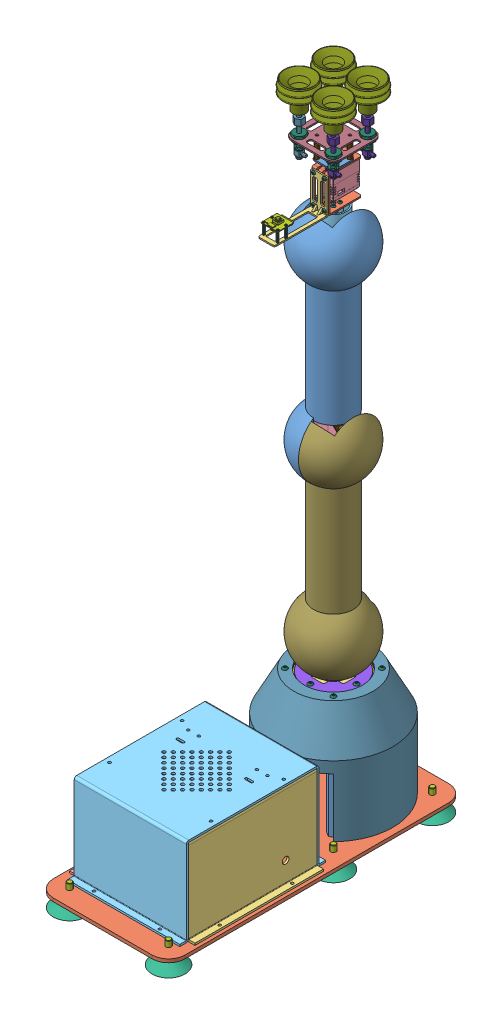
SolidWorks assembly 机械臂1.0, configuration 默认. Lengths in mm.
Overall size (254.56 964.15 483.5).
293 component instances, 44 part files, 11 mates.
Components (placement in the parent):
- 云台-1: 云台 [默认] at origin size (254.56 222.8 254.56) (flexible)
  - M8×100铜柱-1: M8×100铜柱 [默认] at (-52.0858 0 -53.9281) x (0 0 1) z (-1 0 0) size (15.01 100 13)
  - M8×100铜柱-2: M8×100铜柱 [默认] at (53.9802 0 -53.9281) x (0 0 1) z (-1 0 0) size (15.01 100 13)
  - M8×100铜柱-3: M8×100铜柱 [默认] at (53.9802 0 52.1379) x (0 0 1) z (-1 0 0) size (15.01 100 13)
  - M8×100铜柱-4: M8×100铜柱 [默认] at (-52.0858 0 52.1379) x (0 0 1) z (-1 0 0) size (15.01 100 13)
  - 6号舵机底座-1: 6号舵机底座 [默认] at (0 103 0) size (174 3 174)
  - 轴承底座-1: 轴承底座 [默认] at (0 148.8 0) x (-1 0 0) z (0 0 -1) size (82 2 84)
  - 舵机-1: 舵机 [默认] at (0 103 -9.65) x (0 0 1) z (-1 0 0) size (40 51.4 20)
  - 主舵盘-1: 主舵盘 [默认] at (0 143.8 0) x (0 0 1) z (-1 0 0) size (20 5 20)
  - 轴承外底座-1: 轴承外底座 [默认] at (0 148.8 0) x (0 0 1) z (-1 0 0) size (120 2 120)
  - 轴承-1: 轴承 [默认] at (0 148.8 0) x (-0.002471 0 0.999997) z (-0.999997 0 -0.002471) size (100 10 100)
  - 轴承顶-1: 轴承顶 [默认] at (0 160.8 0) x (-1 0 0) z (0 0 -1) size (84 2 84)
  - 轴承外顶-1: 轴承外顶 [默认] at (0 160.8 0) x (-1 0 0) z (0 0 -1) size (120 2 120)
  - 大U支架-1: 大U支架 [默认] at (0 182.8 0) x (-1 0 0) z (0 0 -1) size (51.6 42 40)
  - 镙丝 PA2x12-半圆头十字(自攻)-6: 镙丝 PA2x12-半圆头十字(自攻) [默认] at (-8 150 0) x (0.999316 0 -0.036972) z (0.036972 0 0.999316) size (3.55 13.42 3.55)
  - 镙丝 PA2x12-半圆头十字(自攻)-7: 镙丝 PA2x12-半圆头十字(自攻) [默认] at (-5.6569 150 -5.6569) x (0.776673 0 0.629905) z (-0.629905 0 0.776673) size (3.55 13.42 3.55)
  - 镙丝 PA2x12-半圆头十字(自攻)-8: 镙丝 PA2x12-半圆头十字(自攻) [默认] at (0 150 -8) x (0 0 1) z (-1 0 0) size (3.55 13.42 3.55)
  - 镙丝 PA2x12-半圆头十字(自攻)-9: 镙丝 PA2x12-半圆头十字(自攻) [默认] at (5.6569 150 -5.6569) x (0 0 1) z (-1 0 0) size (3.55 13.42 3.55)
  - 镙丝 PA2x12-半圆头十字(自攻)-10: 镙丝 PA2x12-半圆头十字(自攻) [默认] at (8 150 0) x (0 0 1) z (-1 0 0) size (3.55 13.42 3.55)
  - 镙丝 PA2x12-半圆头十字(自攻)-11: 镙丝 PA2x12-半圆头十字(自攻) [默认] at (5.6569 150 5.6569) x (0.961264 0 -0.275631) z (0.275631 0 0.961264) size (3.55 13.42 3.55)
  - 镙丝 PA2x12-半圆头十字(自攻)-12: 镙丝 PA2x12-半圆头十字(自攻) [默认] at (0 150 8) x (0.931957 0 -0.36257) z (0.36257 0 0.931957) size (3.55 13.42 3.55)
  - 镙丝 PA2x12-半圆头十字(自攻)-13: 镙丝 PA2x12-半圆头十字(自攻) [默认] at (-5.6569 150 5.6569) x (0.711428 0 -0.702759) z (0.702759 0 0.711428) size (3.55 13.42 3.55)
  - 镙丝 PA3x12-半圆头十字(自攻)-1: 镙丝 PA3x12-半圆头十字(自攻) [默认] at (0 150.8 0) x (0 0 1) z (-1 0 0) size (5.3 14.31 5.3)
  - 12号舵机连接管-1: 12号舵机连接管 [默认] at (0 160.8 0) x (0 0 1) z (-1 0 0) size (40 20 40)
  - 云台外壳-1: 云台外壳 [默认] at (0 160.8 0) x (0.707107 0 0.707107) z (-0.707107 0 0.707107) size (180 163.8 180)
  - hexagon socket button head screws gb-34: hexagon socket button head screws gb [GB_SOCKET_TYPE7 M4X16-N] at (35 163 0) x (0 -1 0) z (-1 0 0) size (18.2 7.6 7.6)
  - hexagon socket button head screws gb-35: hexagon socket button head screws gb [GB_SOCKET_TYPE7 M4X16-N] at (0 163 -35) x (0 -1 0) z (-1 0 0) size (18.2 7.6 7.6)
  - hexagon socket button head screws gb-36: hexagon socket button head screws gb [GB_SOCKET_TYPE7 M4X16-N] at (0 163 35) x (0 -1 0) z (-1 0 0) size (18.2 7.6 7.6)
  - hexagon socket button head screws gb-37: hexagon socket button head screws gb [GB_SOCKET_TYPE7 M4X16-N] at (-35 163 0) x (0 -1 0) z (-1 0 0) size (18.2 7.6 7.6)
  - hexagon socket button head screws gb-38: hexagon socket button head screws gb [GB_SOCKET_TYPE7 M4X16-N] at (36.7696 166 36.7696) x (0 -1 0) z (-1 0 0) size (18.2 7.6 7.6)
  - hexagon socket button head screws gb-39: hexagon socket button head screws gb [GB_SOCKET_TYPE7 M4X16-N] at (36.7696 166 -36.7696) x (0 -1 0) z (-1 0 0) size (18.2 7.6 7.6)
  - hexagon socket button head screws gb-40: hexagon socket button head screws gb [GB_SOCKET_TYPE7 M4X16-N] at (-36.7696 166 -36.7696) x (0 -1 0) z (-1 0 0) size (18.2 7.6 7.6)
  - hexagon socket button head screws gb-41: hexagon socket button head screws gb [GB_SOCKET_TYPE7 M4X16-N] at (-36.7696 166 36.7696) x (0 -1 0) z (-1 0 0) size (18.2 7.6 7.6)
  - hexagon socket button head screws gb-42: hexagon socket button head screws gb [GB_SOCKET_TYPE7 M4X16-N] at (5 185 5) x (0 -1 0) z (-1 0 0) size (18.2 7.6 7.6)
  - hexagon socket button head screws gb-43: hexagon socket button head screws gb [GB_SOCKET_TYPE7 M4X16-N] at (5 185 -5) x (0 -1 0) z (-1 0 0) size (18.2 7.6 7.6)
  - hexagon socket button head screws gb-44: hexagon socket button head screws gb [GB_SOCKET_TYPE7 M4X16-N] at (-5 185 5) x (0 -1 0) z (-1 0 0) size (18.2 7.6 7.6)
  - hexagon socket button head screws gb-45: hexagon socket button head screws gb [GB_SOCKET_TYPE7 M4X16-N] at (-5 185 -5) x (0 -1 0) z (-1 0 0) size (18.2 7.6 7.6)
  - hexagon socket button head screws gb-47: hexagon socket button head screws gb [GB_SOCKET_TYPE7 M8X40-N] at (-53.033 110.4 -53.033) x (0 -1 0) z (-1 0 0) size (44.4 14 14)
  - hexagon socket button head screws gb-48: hexagon socket button head screws gb [GB_SOCKET_TYPE7 M8X40-N] at (53.033 110.4 -53.033) x (0 -1 0) z (-1 0 0) size (44.4 14 14)
  - hexagon socket button head screws gb-49: hexagon socket button head screws gb [GB_SOCKET_TYPE7 M8X40-N] at (53.033 110.4 53.033) x (0 -1 0) z (-1 0 0) size (44.4 14 14)
  - hexagon socket button head screws gb-50: hexagon socket button head screws gb [GB_SOCKET_TYPE7 M8X40-N] at (-53.033 110.4 53.033) x (0 -1 0) z (-1 0 0) size (44.4 14 14)
  - 镙丝 PM2x8-半圆头-1: 镙丝 PM2x8-半圆头 [默认] at (-8 98.8 -9.15) x (-0.546944 0 0.837169) z (0.837169 0 0.546944) size (3.55 9.32 3.55)
  - 镙丝 PM2x8-半圆头-2: 镙丝 PM2x8-半圆头 [默认] at (-7 98.8 -20.15) x (-0.546944 0 0.837169) z (0.837169 0 0.546944) size (3.55 9.32 3.55)
  - 镙丝 PM2x8-半圆头-3: 镙丝 PM2x8-半圆头 [默认] at (8 98.8 -9.15) x (-0.546944 0 0.837169) z (0.837169 0 0.546944) size (3.55 9.32 3.55)
  - 镙丝 PM2x8-半圆头-4: 镙丝 PM2x8-半圆头 [默认] at (7 98.8 -20.15) x (-0.546944 0 0.837169) z (0.837169 0 0.546944) size (3.55 9.32 3.55)
  - 镙丝 PM2x8-半圆头-5: 镙丝 PM2x8-半圆头 [默认] at (0 98.8 -27.15) x (-0.546944 0 0.837169) z (0.837169 0 0.546944) size (3.55 9.32 3.55)
- 机械臂-1: 机械臂 [默认] at (-53.1 220.673 0) x (0 0 -1) z (1 0 0) size (149.99 632.89 106) (flexible)
  - 舵机-2: 舵机 [默认] at (0 1.777 33.1) x (0 -1 0) z (-1 0 0) size (43.48 52.6 27.66) (flexible)
    - 舵机-1: 舵机 [默认] at origin size (40 51.4 20)
    - 副舵盘-1: 副舵盘 [默认] at (9.65 -0.8 0) x (-0.707107 0 -0.707107) z (-0.707107 0 0.707107) size (20 5 20)
    - 主舵盘-1: 主舵盘 [默认] at (9.65 40.8 0) x (-0.119517 0 0.992832) z (-0.992832 0 -0.119517) size (20 5 20)
  - 短U支架-1: 短U支架 [默认] at (0 29.777 53.1) x (0 0 1) z (1 0 0) size (44 22 40)
  - 舵机-3: 舵机 [默认] at (0 253.427 33.1) x (0 -1 0) z (-1 0 0) size (43.48 52.6 27.66) (flexible)
    - 舵机-1: 舵机 [默认] at origin size (40 51.4 20)
    - 副舵盘-1: 副舵盘 [默认] at (9.65 -0.8 0) x (0.998338 0 -0.057634) z (-0.057634 0 -0.998338) size (20 5 20)
    - 主舵盘-1: 主舵盘 [默认] at (9.65 40.8 0) x (-0.770235 0 -0.63776) z (0.63776 0 -0.770235) size (20 5 20)
  - 短U支架-2: 短U支架 [默认] at (0 281.427 53.1) x (0 0 1) z (1 0 0) size (44 22 40)
  - 120cm连接管-2: 120cm连接管 [默认] at (0 463.427 53.1) x (0 0 -1) z (-1 0 0) size (106 351.73 100.99)
  - 舵机-5: 舵机 [默认] at (0 505.077 33.1) x (0 -1 0) z (-1 0 0) size (43.48 52.6 27.66) (flexible)
    - 舵机-1: 舵机 [默认] at origin size (40 51.4 20)
    - 副舵盘-1: 副舵盘 [默认] at (9.65 -0.8 0) x (-0.661524 0 0.749924) z (0.749924 0 0.661524) size (20 5 20)
    - 主舵盘-1: 主舵盘 [默认] at (9.65 40.8 0) x (0.634107 0 -0.773246) z (0.773246 0 0.634107) size (20 5 20)
  - 短U支架-3: 短U支架 [默认] at (0 533.077 53.1) x (0 0 1) z (1 0 0) size (44 22 40)
  - 转向舵机支架-1: 转向舵机支架 [默认] at (-18 580.077 53.1) x (0 -1 0) z (0 0 -1) size (54 50.65 25)
  - 舵机-7: 舵机 [默认] at (9.65 565.077 53.1) x (-1 0 0) z (0 0 -1) size (40 51.4 20)
  - 主舵盘-1: 主舵盘 [默认] at (0 605.877 53.1) size (20 5 20)
  - 摄像头支架-1: 摄像头支架 [默认] at (-22 580.077 53.1) x (0 -1 0) z (0 0 -1) size (52 82 25)
  - 镙丝 PM2x4-半圆头-1: 镙丝 PM2x4-半圆头 [默认] at (-7 515.577 76.3) x (0.766466 0.642285 0) z (0.642285 -0.766466 0) size (3.55 5.35 3.55)
  - 镙丝 PM2x4-半圆头-2: 镙丝 PM2x4-半圆头 [默认] at (7 515.577 76.3) x (0.766466 0.642285 0) z (0.642285 -0.766466 0) size (3.55 5.35 3.55)
  - 镙丝 PM2x4-半圆头-3: 镙丝 PM2x4-半圆头 [默认] at (7 515.577 29.9) x (0.766466 0.642285 0) z (-0.642285 0.766466 0) size (3.55 5.35 3.55)
  - 镙丝 PM2x4-半圆头-4: 镙丝 PM2x4-半圆头 [默认] at (0 522.577 76.3) x (0.766466 0.642285 0) z (0.642285 -0.766466 0) size (3.55 5.35 3.55)
  - 镙丝 PM2x4-半圆头-5: 镙丝 PM2x4-半圆头 [默认] at (0 522.577 29.9) x (0.766466 0.642285 0) z (-0.642285 0.766466 0) size (3.55 5.35 3.55)
  - 镙丝 PM2x4-半圆头-6: 镙丝 PM2x4-半圆头 [默认] at (-7 515.577 29.9) x (0.766466 0.642285 0) z (-0.642285 0.766466 0) size (3.55 5.35 3.55)
  - 镙丝 PM2x4-半圆头-7: 镙丝 PM2x4-半圆头 [默认] at (-5.6569 489.7701 26.1) x (0.766466 0.642285 0) z (-0.642285 0.766466 0) size (3.55 5.35 3.55)
  - 镙丝 PM2x4-半圆头-8: 镙丝 PM2x4-半圆头 [默认] at (-8 495.427 26.1) x (0.766466 0.642285 0) z (-0.642285 0.766466 0) size (3.55 5.35 3.55)
  - 镙丝 PM2x4-半圆头-9: 镙丝 PM2x4-半圆头 [默认] at (0 503.427 26.1) x (0.766466 0.642285 0) z (-0.642285 0.766466 0) size (3.55 5.35 3.55)
  - 镙丝 PM2x4-半圆头-10: 镙丝 PM2x4-半圆头 [默认] at (-5.6569 501.0838 26.1) x (0.766466 0.642285 0) z (-0.642285 0.766466 0) size (3.55 5.35 3.55)
  - 镙丝 PM2x4-半圆头-11: 镙丝 PM2x4-半圆头 [默认] at (8 495.427 26.1) x (0.766466 0.642285 0) z (-0.642285 0.766466 0) size (3.55 5.35 3.55)
  - 镙丝 PM2x4-半圆头-12: 镙丝 PM2x4-半圆头 [默认] at (5.6569 501.0838 26.1) x (0.766466 0.642285 0) z (-0.642285 0.766466 0) size (3.55 5.35 3.55)
  - 镙丝 PM2x4-半圆头-13: 镙丝 PM2x4-半圆头 [默认] at (-8 495.427 80.1) x (0.766466 0.642285 0) z (0.642285 -0.766466 0) size (3.55 5.35 3.55)
  - 镙丝 PM2x4-半圆头-14: 镙丝 PM2x4-半圆头 [默认] at (0 487.427 80.1) x (0.766466 0.642285 0) z (0.642285 -0.766466 0) size (3.55 5.35 3.55)
  - 镙丝 PM2x4-半圆头-15: 镙丝 PM2x4-半圆头 [默认] at (-5.6569 489.7701 80.1) x (0.766466 0.642285 0) z (0.642285 -0.766466 0) size (3.55 5.35 3.55)
  - 镙丝 PM2x4-半圆头-16: 镙丝 PM2x4-半圆头 [默认] at (5.6569 489.7701 80.1) x (0.766466 0.642285 0) z (0.642285 -0.766466 0) size (3.55 5.35 3.55)
  - 镙丝 PM2x4-半圆头-17: 镙丝 PM2x4-半圆头 [默认] at (-5.6569 501.0838 80.1) x (0.766466 0.642285 0) z (0.642285 -0.766466 0) size (3.55 5.35 3.55)
  - 镙丝 PM2x4-半圆头-18: 镙丝 PM2x4-半圆头 [默认] at (0 503.427 80.1) x (0.766466 0.642285 0) z (0.642285 -0.766466 0) size (3.55 5.35 3.55)
  - 镙丝 PM2x4-半圆头-19: 镙丝 PM2x4-半圆头 [默认] at (20.15 608.277 60.1) x (0.530073 0 0.847952) z (-0.847952 0 0.530073) size (3.55 5.35 3.55)
  - 镙丝 PM2x4-半圆头-20: 镙丝 PM2x4-半圆头 [默认] at (20.15 608.277 46.1) x (0.530073 0 0.847952) z (-0.847952 0 0.530073) size (3.55 5.35 3.55)
  - 镙丝 PM2x4-半圆头-21: 镙丝 PM2x4-半圆头 [默认] at (9.15 608.277 45.1) x (-0.92142 0 0.388568) z (-0.388568 0 -0.92142) size (3.55 5.35 3.55)
  - 镙丝 PM2x4-半圆头-22: 镙丝 PM2x4-半圆头 [默认] at (27.15 608.277 53.1) x (0.530073 0 0.847952) z (-0.847952 0 0.530073) size (3.55 5.35 3.55)
  - 镙丝 PM2x4-半圆头-23: 镙丝 PM2x4-半圆头 [默认] at (9.15 608.277 61.1) x (0.530073 0 0.847952) z (-0.847952 0 0.530073) size (3.55 5.35 3.55)
  - 镙丝 PM2x4-半圆头-24: 镙丝 PM2x4-半圆头 [默认] at (7 263.927 29.9) x (0.766466 0.642285 0) z (-0.642285 0.766466 0) size (3.55 5.35 3.55)
  - 镙丝 PM2x4-半圆头-25: 镙丝 PM2x4-半圆头 [默认] at (0 270.927 29.9) x (0.766466 0.642285 0) z (-0.642285 0.766466 0) size (3.55 5.35 3.55)
  - 镙丝 PM2x4-半圆头-26: 镙丝 PM2x4-半圆头 [默认] at (-7 263.927 29.9) x (0.766466 0.642285 0) z (-0.642285 0.766466 0) size (3.55 5.35 3.55)
  - 镙丝 PM2x4-半圆头-27: 镙丝 PM2x4-半圆头 [默认] at (-5.6569 238.1201 26.1) x (0.766466 0.642285 0) z (-0.642285 0.766466 0) size (3.55 5.35 3.55)
  - 镙丝 PM2x4-半圆头-28: 镙丝 PM2x4-半圆头 [默认] at (-8 243.777 26.1) x (0.766466 0.642285 0) z (-0.642285 0.766466 0) size (3.55 5.35 3.55)
  - 镙丝 PM2x4-半圆头-29: 镙丝 PM2x4-半圆头 [默认] at (0 235.777 26.1) x (0.766466 0.642285 0) z (-0.642285 0.766466 0) size (3.55 5.35 3.55)
  - 镙丝 PM2x4-半圆头-30: 镙丝 PM2x4-半圆头 [默认] at (5.6569 238.1201 26.1) x (0.766466 0.642285 0) z (-0.642285 0.766466 0) size (3.55 5.35 3.55)
  - 镙丝 PM2x4-半圆头-31: 镙丝 PM2x4-半圆头 [默认] at (0 251.777 26.1) x (0.766466 0.642285 0) z (-0.642285 0.766466 0) size (3.55 5.35 3.55)
  - 镙丝 PM2x4-半圆头-32: 镙丝 PM2x4-半圆头 [默认] at (8 243.777 26.1) x (0.766466 0.642285 0) z (-0.642285 0.766466 0) size (3.55 5.35 3.55)
  - 镙丝 PM2x4-半圆头-33: 镙丝 PM2x4-半圆头 [默认] at (0 251.777 80.1) x (0.766466 0.642285 0) z (0.642285 -0.766466 0) size (3.55 5.35 3.55)
  - 镙丝 PM2x4-半圆头-34: 镙丝 PM2x4-半圆头 [默认] at (8 243.777 80.1) x (0.766466 0.642285 0) z (0.642285 -0.766466 0) size (3.55 5.35 3.55)
  - 镙丝 PM2x4-半圆头-35: 镙丝 PM2x4-半圆头 [默认] at (5.6569 238.1201 80.1) x (0.766466 0.642285 0) z (0.642285 -0.766466 0) size (3.55 5.35 3.55)
  - 镙丝 PM2x4-半圆头-36: 镙丝 PM2x4-半圆头 [默认] at (-5.6569 238.1201 80.1) x (0.766466 0.642285 0) z (0.642285 -0.766466 0) size (3.55 5.35 3.55)
  - 镙丝 PM2x4-半圆头-37: 镙丝 PM2x4-半圆头 [默认] at (0 235.777 80.1) x (0.766466 0.642285 0) z (0.642285 -0.766466 0) size (3.55 5.35 3.55)
  - 镙丝 PM2x4-半圆头-38: 镙丝 PM2x4-半圆头 [默认] at (5.6569 249.4338 80.1) x (0.766466 0.642285 0) z (0.642285 -0.766466 0) size (3.55 5.35 3.55)
  - 镙丝 PM2x4-半圆头-39: 镙丝 PM2x4-半圆头 [默认] at (-7 263.927 76.3) x (0.766466 0.642285 0) z (0.642285 -0.766466 0) size (3.55 5.35 3.55)
  - 镙丝 PM2x4-半圆头-40: 镙丝 PM2x4-半圆头 [默认] at (0 270.927 76.3) x (0.766466 0.642285 0) z (0.642285 -0.766466 0) size (3.55 5.35 3.55)
  - 镙丝 PM2x4-半圆头-41: 镙丝 PM2x4-半圆头 [默认] at (7 263.927 76.3) x (0.766466 0.642285 0) z (0.642285 -0.766466 0) size (3.55 5.35 3.55)
  - 镙丝 PM2x4-半圆头-42: 镙丝 PM2x4-半圆头 [默认] at (-7 12.277 76.3) x (0.766466 0.642285 0) z (0.642285 -0.766466 0) size (3.55 5.35 3.55)
  - 镙丝 PM2x4-半圆头-43: 镙丝 PM2x4-半圆头 [默认] at (0 19.277 76.3) x (0.766466 0.642285 0) z (0.642285 -0.766466 0) size (3.55 5.35 3.55)
  - 镙丝 PM2x4-半圆头-44: 镙丝 PM2x4-半圆头 [默认] at (7 12.277 76.3) x (0.766466 0.642285 0) z (0.642285 -0.766466 0) size (3.55 5.35 3.55)
  - 镙丝 PM2x4-半圆头-45: 镙丝 PM2x4-半圆头 [默认] at (-7.9427 -6.9169 78.1) x (0.766466 0.642285 0) z (0.642285 -0.766466 0) size (3.55 5.35 3.55)
  - 镙丝 PM2x4-半圆头-46: 镙丝 PM2x4-半圆头 [默认] at (-4.9402 -1.5807 78.1) x (0.766466 0.642285 0) z (0.642285 -0.766466 0) size (3.55 5.35 3.55)
  - 镙丝 PM2x4-半圆头-47: 镙丝 PM2x4-半圆头 [默认] at (-6.2924 -12.8133 78.1) x (0.766466 0.642285 0) z (0.642285 -0.766466 0) size (3.55 5.35 3.55)
  - 镙丝 PM2x4-半圆头-48: 镙丝 PM2x4-半圆头 [默认] at (7.9427 -8.8292 78.1) x (0.766466 0.642285 0) z (0.642285 -0.766466 0) size (3.55 5.35 3.55)
  - 镙丝 PM2x4-半圆头-49: 镙丝 PM2x4-半圆头 [默认] at (-0.9561 -15.8157 78.1) x (0.766466 0.642285 0) z (0.642285 -0.766466 0) size (3.55 5.35 3.55)
  - 镙丝 PM2x4-半圆头-50: 镙丝 PM2x4-半圆头 [默认] at (4.9402 -14.1654 78.1) x (0.766466 0.642285 0) z (0.642285 -0.766466 0) size (3.55 5.35 3.55)
  - 镙丝 PM2x4-半圆头-51: 镙丝 PM2x4-半圆头 [默认] at (8 -7.873 28.1) x (0.766466 0.642285 0) z (-0.642285 0.766466 0) size (3.55 5.35 3.55)
  - 镙丝 PM2x4-半圆头-52: 镙丝 PM2x4-半圆头 [默认] at (5.6569 -13.5299 28.1) x (0.766466 0.642285 0) z (-0.642285 0.766466 0) size (3.55 5.35 3.55)
  - 镙丝 PM2x4-半圆头-53: 镙丝 PM2x4-半圆头 [默认] at (0 0.127 28.1) x (0.766466 0.642285 0) z (-0.642285 0.766466 0) size (3.55 5.35 3.55)
  - 镙丝 PM2x4-半圆头-54: 镙丝 PM2x4-半圆头 [默认] at (5.6569 -2.2162 28.1) x (0.726811 0.686838 0) z (-0.686838 0.726811 0) size (3.55 5.35 3.55)
  - 镙丝 PM2x4-半圆头-55: 镙丝 PM2x4-半圆头 [默认] at (-5.6569 -2.2162 28.1) x (0.766466 0.642285 0) z (-0.642285 0.766466 0) size (3.55 5.35 3.55)
  - 镙丝 PM2x4-半圆头-56: 镙丝 PM2x4-半圆头 [默认] at (0 -15.873 28.1) x (0.766466 0.642285 0) z (-0.642285 0.766466 0) size (3.55 5.35 3.55)
  - 镙丝 PM2x4-半圆头-57: 镙丝 PM2x4-半圆头 [默认] at (7 12.277 29.9) x (0.766466 0.642285 0) z (-0.642285 0.766466 0) size (3.55 5.35 3.55)
  - 镙丝 PM2x4-半圆头-58: 镙丝 PM2x4-半圆头 [默认] at (0 19.277 29.9) x (0.766466 0.642285 0) z (-0.642285 0.766466 0) size (3.55 5.35 3.55)
  - 镙丝 PM2x4-半圆头-59: 镙丝 PM2x4-半圆头 [默认] at (-7 12.277 29.9) x (0.766466 0.642285 0) z (-0.642285 0.766466 0) size (3.55 5.35 3.55)
  - 镙丝 PM2x4-半圆头-60: 镙丝 PM2x4-半圆头 [默认] at (-8 -7.873 28.1) x (-0.461979 -0.886891 0) z (0.886891 -0.461979 0) size (3.55 5.35 3.55)
  - 镙丝 PM2x4-半圆头-61: 镙丝 PM2x4-半圆头 [默认] at (-5.6569 -13.5299 28.1) x (-0.461979 -0.886891 0) z (0.886891 -0.461979 0) size (3.55 5.35 3.55)
  - 镙丝 PM2x4-半圆头-62: 镙丝 PM2x4-半圆头 [默认] at (6.2924 -2.9328 78.1) x (-0.461979 -0.886891 0) z (-0.886891 0.461979 0) size (3.55 5.35 3.55)
  - 镙丝 PM2x4-半圆头-63: 镙丝 PM2x4-半圆头 [默认] at (0.9561 0.0696 78.1) x (-0.461979 -0.886891 0) z (-0.886891 0.461979 0) size (3.55 5.35 3.55)
  - 镙丝 PM2x4-半圆头-64: 镙丝 PM2x4-半圆头 [默认] at (-8 243.777 80.1) x (-0.461979 -0.886891 0) z (-0.886891 0.461979 0) size (3.55 5.35 3.55)
  - 镙丝 PM2x4-半圆头-65: 镙丝 PM2x4-半圆头 [默认] at (-5.6569 249.4338 80.1) x (-0.461979 -0.886891 0) z (-0.886891 0.461979 0) size (3.55 5.35 3.55)
  - 镙丝 PM2x4-半圆头-66: 镙丝 PM2x4-半圆头 [默认] at (-5.6569 249.4338 26.1) x (-0.458589 -0.888648 0) z (0.888648 -0.458589 0) size (3.55 5.35 3.55)
  - 镙丝 PM2x4-半圆头-67: 镙丝 PM2x4-半圆头 [默认] at (5.6569 249.4338 26.1) x (-0.461979 -0.886891 0) z (0.886891 -0.461979 0) size (3.55 5.35 3.55)
  - 镙丝 PM2x4-半圆头-68: 镙丝 PM2x4-半圆头 [默认] at (5.6569 501.0838 80.1) x (-0.487544 -0.873098 0) z (-0.873098 0.487544 0) size (3.55 5.35 3.55)
  - 镙丝 PM2x4-半圆头-69: 镙丝 PM2x4-半圆头 [默认] at (8 495.427 80.1) x (-0.461979 -0.886891 0) z (-0.886891 0.461979 0) size (3.55 5.35 3.55)
  - 镙丝 PM2x4-半圆头-70: 镙丝 PM2x4-半圆头 [默认] at (5.6569 489.7701 26.1) x (-0.461979 -0.886891 0) z (0.886891 -0.461979 0) size (3.55 5.35 3.55)
  - 镙丝 PM2x4-半圆头-71: 镙丝 PM2x4-半圆头 [默认] at (0 487.427 26.1) x (-0.461979 -0.886891 0) z (0.886891 -0.461979 0) size (3.55 5.35 3.55)
  - 60cm连接管-1: 60cm连接管 [默认] at (0 535.077 53.1) x (-1 0 0) z (0 0 -1) size (40 18 40)
  - hexagon socket button head screws gb-2: hexagon socket button head screws gb [GB_SOCKET_TYPE7 M3X12-N] at (-5 215.427 58.1) x (0 -1 0) z (-0.057594 0 -0.99834) size (13.65 5.7 5.7)
  - hexagon socket button head screws gb-3: hexagon socket button head screws gb [GB_SOCKET_TYPE7 M3X12-N] at (5 215.427 58.1) x (0 -1 0) z (-0.057594 0 -0.99834) size (13.65 5.7 5.7)
  - hexagon socket button head screws gb-4: hexagon socket button head screws gb [GB_SOCKET_TYPE7 M3X12-N] at (5 215.427 48.1) x (0 -1 0) z (-0.057594 0 -0.99834) size (13.65 5.7 5.7)
  - hexagon socket button head screws gb-5: hexagon socket button head screws gb [GB_SOCKET_TYPE7 M3X12-N] at (-5 215.427 48.1) x (0 -1 0) z (-0.057594 0 -0.99834) size (13.65 5.7 5.7)
  - hexagon socket button head screws gb-6: hexagon socket button head screws gb [GB_SOCKET_TYPE7 M3X12-N] at (-5 467.077 58.1) x (0 -1 0) z (0.893954 0 -0.448158) size (13.65 5.7 5.7)
  - hexagon socket button head screws gb-7: hexagon socket button head screws gb [GB_SOCKET_TYPE7 M3X12-N] at (5 467.077 58.1) x (0 -1 0) z (0.893954 0 -0.448158) size (13.65 5.7 5.7)
  - hexagon socket button head screws gb-8: hexagon socket button head screws gb [GB_SOCKET_TYPE7 M3X12-N] at (5 467.077 48.1) x (0 -1 0) z (0.893954 0 -0.448158) size (13.65 5.7 5.7)
  - hexagon socket button head screws gb-9: hexagon socket button head screws gb [GB_SOCKET_TYPE7 M3X12-N] at (-5 467.077 48.1) x (0 -1 0) z (0.893954 0 -0.448158) size (13.65 5.7 5.7)
  - hexagon socket button head screws gb-10: hexagon socket button head screws gb [GB_SOCKET_TYPE7 M3X12-N] at (5 556.727 48.1) x (0 -1 0) z (-0.847952 0 0.530073) size (13.65 5.7 5.7)
  - hexagon socket button head screws gb-11: hexagon socket button head screws gb [GB_SOCKET_TYPE7 M3X12-N] at (-5 556.727 48.1) x (0 -1 0) z (-0.847952 0 0.530073) size (13.65 5.7 5.7)
  - hexagon socket button head screws gb-12: hexagon socket button head screws gb [GB_SOCKET_TYPE7 M3X12-N] at (-5 556.727 58.1) x (0 -1 0) z (-0.847952 0 0.530073) size (13.65 5.7 5.7)
  - hexagon socket button head screws gb-13: hexagon socket button head screws gb [GB_SOCKET_TYPE7 M3X12-N] at (5 556.727 58.1) x (0 -1 0) z (-0.847952 0 0.530073) size (13.65 5.7 5.7)
  - hexagon socket button head screws gb-15: hexagon socket button head screws gb [GB_SOCKET_TYPE7 M3X8-N] at (0 495.427 80.55) x (0 0 -1) z (0.899576 0.436764 0) size (9.65 5.7 5.7)
  - hexagon socket button head screws gb-16: hexagon socket button head screws gb [GB_SOCKET_TYPE7 M3X8-N] at (0 243.777 80.55) x (0 0 -1) z (0.911973 0.41025 0) size (9.65 5.7 5.7)
  - hexagon socket button head screws gb-17: hexagon socket button head screws gb [GB_SOCKET_TYPE7 M3X8-N] at (0 -7.873 80.55) x (0 0 -1) z (0.911973 0.41025 0) size (9.65 5.7 5.7)
  - hexagon socket button head screws gb-18: hexagon socket button head screws gb [GB_SOCKET_TYPE7 M3X6-N] at (-23.65 601.077 61.1) x (1 0 0) z (0 -0.722297 0.691583) size (7.65 5.7 5.7)
  - hexagon socket button head screws gb-19: hexagon socket button head screws gb [GB_SOCKET_TYPE7 M3X6-N] at (-23.65 601.077 45.1) x (1 0 0) z (0 -0.722297 0.691583) size (7.65 5.7 5.7)
  - hexagon socket button head screws gb-20: hexagon socket button head screws gb [GB_SOCKET_TYPE7 M3X6-N] at (-23.65 559.077 61.1) x (1 0 0) z (0 -0.722297 0.691583) size (7.65 5.7 5.7)
  - hexagon socket button head screws gb-21: hexagon socket button head screws gb [GB_SOCKET_TYPE7 M3X6-N] at (-23.65 559.077 45.1) x (1 0 0) z (0 -0.722297 0.691583) size (7.65 5.7 5.7)
  - M2×10铜柱-1: M2×10铜柱 [默认] at (-95 555.077 63.6) x (0.530073 0 0.847952) z (-0.847952 0 0.530073) size (3.2 15 3.2)
  - M2×10铜柱-2: M2×10铜柱 [默认] at (-82.5 555.077 63.6) x (0.530073 0 0.847952) z (-0.847952 0 0.530073) size (3.2 15 3.2)
  - M2×10铜柱-3: M2×10铜柱 [默认] at (-95 555.077 42.6) x (0.530073 0 0.847952) z (-0.847952 0 0.530073) size (3.2 15 3.2)
  - M2×10铜柱-4: M2×10铜柱 [默认] at (-82.5 555.077 42.6) x (0.530073 0 0.847952) z (-0.847952 0 0.530073) size (3.2 15 3.2)
  - 摄像头-1: 摄像头 [默认] at (-85 570.077 53.1) x (0 0 -1) z (1 0 0) size (25 9.2 28)
    - 摄像头-1: 摄像头 [默认] at origin size (25 9.2 28)
    - 0603电容-2: 0603电容 [默认] at (-25.6955 -0.01 -49.0268) x (1 0 0) z (0 -1 0) size (1.6 0.82 0.82)
      - C_0603^0603电容-1: C_0603^0603电容 [默认] at (34.005 43.815 0) x (-1 0 0) z (0 0 1) size (1.6 0.82 0.82) (virtual)
        - C_0603-9^C_0603_0603电容-1: C_0603-9^C_0603_0603电容 [默认] at origin size (1.6 0.82 0.82) (virtual)
    - 0603电容-3: 0603电容 [默认] at (-42.3062 -0.01 -47.0667) x (1 0 0) z (0 -1 0) size (1.6 0.82 0.82)
      - C_0603^0603电容-1: C_0603^0603电容 [默认] at (34.005 43.815 0) x (-1 0 0) z (0 0 1) size (1.6 0.82 0.82) (virtual)
        - C_0603-9^C_0603_0603电容-1: C_0603-9^C_0603_0603电容 [默认] at origin size (1.6 0.82 0.82) (virtual)
    - 0603电容-7: 0603电容 [默认] at (49.2456 -0.01 -38.1328) x (0 0 1) z (0 -1 0) size (1.6 0.82 0.82)
      - C_0603^0603电容-1: C_0603^0603电容 [默认] at (34.005 43.815 0) x (-1 0 0) z (0 0 1) size (1.6 0.82 0.82) (virtual)
        - C_0603-9^C_0603_0603电容-1: C_0603-9^C_0603_0603电容 [默认] at origin size (1.6 0.82 0.82) (virtual)
    - 0603电容-10: 0603电容 [默认] at (-25.4606 -0.01 -42.7048) x (1 0 0) z (0 -1 0) size (1.6 0.82 0.82)
      - C_0603^0603电容-1: C_0603^0603电容 [默认] at (34.005 43.815 0) x (-1 0 0) z (0 0 1) size (1.6 0.82 0.82) (virtual)
        - C_0603-9^C_0603_0603电容-1: C_0603-9^C_0603_0603电容 [默认] at origin size (1.6 0.82 0.82) (virtual)
    - 0603电容-12: 0603电容 [默认] at (-26.2671 -0.01 -53.9256) x (1 0 0) z (0 -1 0) size (1.6 0.82 0.82)
      - C_0603^0603电容-1: C_0603^0603电容 [默认] at (34.005 43.815 0) x (-1 0 0) z (0 0 1) size (1.6 0.82 0.82) (virtual)
        - C_0603-9^C_0603_0603电容-1: C_0603-9^C_0603_0603电容 [默认] at origin size (1.6 0.82 0.82) (virtual)
    - 0805电容-1: 0805电容 [默认] at (51.4431 -0.01 78.819) x (-1 0 0) z (0 -1 0) size (1.22 2 0.52)
      - C_0805^0805电容-1: C_0805^0805电容 [默认] at (59.563 77.597 0) x (0 1 0) z (0 0 1) size (2 1.22 0.52) (virtual)
        - C_0805-5^C_0805_0805电容-1: C_0805-5^C_0805_0805电容 [默认] at origin size (2 1.22 0.52) (virtual)
    - 0805电阻-1: 0805电阻 [默认] at (115.7364 0 -119.6397) x (0 0 1) z (0 -1 0) size (1.25 2 0.5)
      - R_0805^0805电阻-1: R_0805^0805电阻 [默认] at (112.776 107.442 0) x (0 1 0) z (0 0 1) size (2 1.25 0.5) (virtual)
        - R_0805-21^R_0805_0805电阻-1: R_0805-21^R_0805_0805电阻 [默认] at origin size (2 1.25 0.5) (virtual)
    - 0603电阻-3: 0603电阻 [默认] at (118.0517 0 -149.4378) x (0 0 1) z (0 -1 0) size (0.8 1.6 0.4)
      - R_0603^0603电阻-1: R_0603^0603电阻 [默认] at (138.684 113.411 0) x (0 1 0) z (0 0 1) size (1.6 0.8 0.4) (virtual)
        - R_0603-25^R_0603_0603电阻-1: R_0603-25^R_0603_0603电阻 [默认] at origin size (1.6 0.8 0.4) (virtual)
    - 0603电阻-4: 0603电阻 [默认] at (-106.3314 1 -147.3108) x (0 0 1) z (0 1 0) size (0.8 1.6 0.4)
      - R_0603^0603电阻-1: R_0603^0603电阻 [默认] at (138.684 113.411 0) x (0 1 0) z (0 0 1) size (1.6 0.8 0.4) (virtual)
        - R_0603-25^R_0603_0603电阻-1: R_0603-25^R_0603_0603电阻 [默认] at origin size (1.6 0.8 0.4) (virtual)
    - 0603电阻-5: 0603电阻 [默认] at (134.1937 0 114.6319) x (-1 0 0) z (0 -1 0) size (0.8 1.6 0.4)
      - R_0603^0603电阻-1: R_0603^0603电阻 [默认] at (138.684 113.411 0) x (0 1 0) z (0 0 1) size (1.6 0.8 0.4) (virtual)
        - R_0603-25^R_0603_0603电阻-1: R_0603-25^R_0603_0603电阻 [默认] at origin size (1.6 0.8 0.4) (virtual)
    - 0603电容-14: 0603电容 [默认] at (-26.2671 -0.01 -52.4256) x (1 0 0) z (0 -1 0) size (1.6 0.82 0.82)
      - C_0603^0603电容-1: C_0603^0603电容 [默认] at (34.005 43.815 0) x (-1 0 0) z (0 0 1) size (1.6 0.82 0.82) (virtual)
        - C_0603-9^C_0603_0603电容-1: C_0603-9^C_0603_0603电容 [默认] at origin size (1.6 0.82 0.82) (virtual)
    - 0603电容-15: 0603电容 [默认] at (-30.4606 -0.01 -42.7048) x (1 0 0) z (0 -1 0) size (1.6 0.82 0.82)
      - C_0603^0603电容-1: C_0603^0603电容 [默认] at (34.005 43.815 0) x (-1 0 0) z (0 0 1) size (1.6 0.82 0.82) (virtual)
        - C_0603-9^C_0603_0603电容-1: C_0603-9^C_0603_0603电容 [默认] at origin size (1.6 0.82 0.82) (virtual)
    - 0603电容-16: 0603电容 [默认] at (-35.4606 -0.01 -42.7048) x (1 0 0) z (0 -1 0) size (1.6 0.82 0.82)
      - C_0603^0603电容-1: C_0603^0603电容 [默认] at (34.005 43.815 0) x (-1 0 0) z (0 0 1) size (1.6 0.82 0.82) (virtual)
        - C_0603-9^C_0603_0603电容-1: C_0603-9^C_0603_0603电容 [默认] at origin size (1.6 0.82 0.82) (virtual)
    - 0603电容-17: 0603电容 [默认] at (-37.2671 -0.01 -53.9256) x (1 0 0) z (0 -1 0) size (1.6 0.82 0.82)
      - C_0603^0603电容-1: C_0603^0603电容 [默认] at (34.005 43.815 0) x (-1 0 0) z (0 0 1) size (1.6 0.82 0.82) (virtual)
        - C_0603-9^C_0603_0603电容-1: C_0603-9^C_0603_0603电容 [默认] at origin size (1.6 0.82 0.82) (virtual)
    - 0603电容-18: 0603电容 [默认] at (-37.2671 -0.01 -52.4256) x (1 0 0) z (0 -1 0) size (1.6 0.82 0.82)
      - C_0603^0603电容-1: C_0603^0603电容 [默认] at (34.005 43.815 0) x (-1 0 0) z (0 0 1) size (1.6 0.82 0.82) (virtual)
        - C_0603-9^C_0603_0603电容-1: C_0603-9^C_0603_0603电容 [默认] at origin size (1.6 0.82 0.82) (virtual)
    - 0805电阻-2: 0805电阻 [默认] at (104.7364 0 -119.6397) x (0 0 1) z (0 -1 0) size (1.25 2 0.5)
      - R_0805^0805电阻-1: R_0805^0805电阻 [默认] at (112.776 107.442 0) x (0 1 0) z (0 0 1) size (2 1.25 0.5) (virtual)
        - R_0805-21^R_0805_0805电阻-1: R_0805-21^R_0805_0805电阻 [默认] at origin size (2 1.25 0.5) (virtual)
    - 0603电容-19: 0603电容 [默认] at (-31.1955 -0.01 -49.0268) x (1 0 0) z (0 -1 0) size (1.6 0.82 0.82)
      - C_0603^0603电容-1: C_0603^0603电容 [默认] at (34.005 43.815 0) x (-1 0 0) z (0 0 1) size (1.6 0.82 0.82) (virtual)
        - C_0603-9^C_0603_0603电容-1: C_0603-9^C_0603_0603电容 [默认] at origin size (1.6 0.82 0.82) (virtual)
    - 0603电容-20: 0603电容 [默认] at (-36.6955 -0.01 -49.0268) x (1 0 0) z (0 -1 0) size (1.6 0.82 0.82)
      - C_0603^0603电容-1: C_0603^0603电容 [默认] at (34.005 43.815 0) x (-1 0 0) z (0 0 1) size (1.6 0.82 0.82) (virtual)
        - C_0603-9^C_0603_0603电容-1: C_0603-9^C_0603_0603电容 [默认] at origin size (1.6 0.82 0.82) (virtual)
    - 0603电容-21: 0603电容 [默认] at (43.7456 -0.01 -38.1328) x (0 0 1) z (0 -1 0) size (1.6 0.82 0.82)
      - C_0603^0603电容-1: C_0603^0603电容 [默认] at (34.005 43.815 0) x (-1 0 0) z (0 0 1) size (1.6 0.82 0.82) (virtual)
        - C_0603-9^C_0603_0603电容-1: C_0603-9^C_0603_0603电容 [默认] at origin size (1.6 0.82 0.82) (virtual)
    - 0603电容-22: 0603电容 [默认] at (38.2456 -0.01 -38.1328) x (0 0 1) z (0 -1 0) size (1.6 0.82 0.82)
      - C_0603^0603电容-1: C_0603^0603电容 [默认] at (34.005 43.815 0) x (-1 0 0) z (0 0 1) size (1.6 0.82 0.82) (virtual)
        - C_0603-9^C_0603_0603电容-1: C_0603-9^C_0603_0603电容 [默认] at origin size (1.6 0.82 0.82) (virtual)
    - 0603电阻-6: 0603电阻 [默认] at (132.6937 0 114.6319) x (-1 0 0) z (0 -1 0) size (0.8 1.6 0.4)
      - R_0603^0603电阻-1: R_0603^0603电阻 [默认] at (138.684 113.411 0) x (0 1 0) z (0 0 1) size (1.6 0.8 0.4) (virtual)
        - R_0603-25^R_0603_0603电阻-1: R_0603-25^R_0603_0603电阻 [默认] at origin size (1.6 0.8 0.4) (virtual)
  - 大U支架-1: 大U支架 [默认] at (0 465.427 53.1) x (0 0 1) z (-1 0 0) size (51.6 42 40)
  - 大U支架-2: 大U支架 [默认] at (0 213.777 53.1) x (0 0 -1) z (1 0 0) size (51.6 42 40)
  - 镙丝 PA2x12-半圆头十字(自攻)-1: 镙丝 PA2x12-半圆头十字(自攻) [默认] at (-95 572.277 42.6) x (0.998804 0 0.04889) z (-0.04889 0 0.998804) size (3.55 13.42 3.55)
  - 镙丝 PA2x12-半圆头十字(自攻)-2: 镙丝 PA2x12-半圆头十字(自攻) [默认] at (-82.5 572.277 42.6) x (0.998569 0 0.053471) z (-0.053471 0 0.998569) size (3.55 13.42 3.55)
  - 镙丝 PA2x12-半圆头十字(自攻)-3: 镙丝 PA2x12-半圆头十字(自攻) [默认] at (-95 572.277 63.6) x (0.998569 0 0.053471) z (-0.053471 0 0.998569) size (3.55 13.42 3.55)
  - 镙丝 PA2x12-半圆头十字(自攻)-4: 镙丝 PA2x12-半圆头十字(自攻) [默认] at (-82.5 572.277 63.6) x (0.998569 0 0.053471) z (-0.053471 0 0.998569) size (3.55 13.42 3.55)
  - 23号舵机连接管-1: 23号舵机连接管 [默认] at (0 31.777 53.1) x (0 0 1) z (-1 0 0) size (106 343.73 100.99)
- 连杆吸盘-1: 连杆吸盘 [默认] at (0 862.05 0) x (0 0 1) z (1 0 0) size (103.52 112.99 102.45)
  - 吸盘支架-1: 吸盘支架 [默认] at origin size (75 2 75)
  - 继手-1: 继手 [默认] at (-26 -35.1 -26) size (49.38 104.71 49.38)
    - 继手1-1: 继手1 [默认] at origin size (13.86 62.71 16.6)
    - 继手2-2: 继手2 [默认] at (0 29.1 0) x (0.962822 0 0.270137) z (-0.270137 0 0.962822) size (19.63 21.32 17)
    - MP50吸盘-2: MP50吸盘 [默认] at (0 -15 0) size (49.38 42 49.38)
  - 三通继手-1: 三通继手 [默认] at (-26 -35.1 26) size (51.52 104.71 51.52)
    - 三通继手1-1: 三通继手1 [默认] at origin size (13.86 62.71 21.2)
    - 继手2-1: 继手2 [默认] at (0 29.1 0) size (19.63 21.32 17)
    - MP50吸盘-1: MP50吸盘 [默认] at (0 -15 0) x (0.999013 0 0.044422) z (-0.044422 0 0.999013) size (49.38 42 49.38)
  - 三通继手-2: 三通继手 [默认] at (26 -35.1 26) size (51.52 104.71 51.52)
    - 三通继手1-1: 三通继手1 [默认] at origin size (13.86 62.71 21.2)
    - 继手2-1: 继手2 [默认] at (0 29.1 0) size (19.63 21.32 17)
    - MP50吸盘-1: MP50吸盘 [默认] at (0 -15 0) x (0.999013 0 0.044422) z (-0.044422 0 0.999013) size (49.38 42 49.38)
  - 继手-2: 继手 [默认] at (26 -35.1 -26) size (49.38 104.71 49.38)
    - 继手1-1: 继手1 [默认] at origin size (13.86 62.71 16.6)
    - 继手2-2: 继手2 [默认] at (0 29.1 0) x (0.962822 0 0.270137) z (-0.270137 0 0.962822) size (19.63 21.32 17)
    - MP50吸盘-2: MP50吸盘 [默认] at (0 -15 0) size (49.38 42 49.38)
  - M4×30铜柱-1: M4×30铜柱 [默认] at (-12.5 0 -12.5) size (6.93 28 6)
  - M4×30铜柱-2: M4×30铜柱 [默认] at (-12.5 0 12.5) size (6.93 28 6)
  - M4×30铜柱-3: M4×30铜柱 [默认] at (12.5 0 -12.5) size (6.93 28 6)
  - M4×30铜柱-4: M4×30铜柱 [默认] at (12.5 0 12.5) x (0.5 0 -0.866025) z (0.866025 0 0.5) size (6.93 28 6)
  - 连接板-2: 连接板 [默认] at (0 30 0) size (33 4.5 33)
  - hexagon socket button head screws gb-1: hexagon socket button head screws gb [GB_SOCKET_TYPE7 M4X16-N] at (12.5 32.2 12.5) x (0 -1 0) z (0 0 1) size (18.2 7.6 7.6)
  - hexagon socket button head screws gb-2: hexagon socket button head screws gb [GB_SOCKET_TYPE7 M4X16-N] at (12.5 32.2 -12.5) x (0 -1 0) z (0 0 1) size (18.2 7.6 7.6)
  - hexagon socket button head screws gb-3: hexagon socket button head screws gb [GB_SOCKET_TYPE7 M4X16-N] at (-12.5 32.2 -12.5) x (0 -1 0) z (0 0 1) size (18.2 7.6 7.6)
  - hexagon socket button head screws gb-4: hexagon socket button head screws gb [GB_SOCKET_TYPE7 M4X16-N] at (-12.5 32.2 12.5) x (0 -1 0) z (0 0 1) size (18.2 7.6 7.6)
  - 镙丝 PM2x8-半圆头-1: 镙丝 PM2x8-半圆头 [默认] at (8 26.8 0) x (-0.999997 0 -0.002253) z (-0.002253 0 0.999997) size (3.55 9.32 3.55)
  - 镙丝 PM2x8-半圆头-2: 镙丝 PM2x8-半圆头 [默认] at (-8 26.8 0) x (-0.981299 0 0.192489) z (0.192489 0 0.981299) size (3.55 9.32 3.55)
  - 镙丝 PM2x8-半圆头-3: 镙丝 PM2x8-半圆头 [默认] at (-5.6569 26.8 -5.6569) x (-0.317723 0 0.948184) z (0.948184 0 0.317723) size (3.55 9.32 3.55)
  - 镙丝 PM2x8-半圆头-4: 镙丝 PM2x8-半圆头 [默认] at (-5.6569 26.8 5.6569) x (-0.996572 0 0.082729) z (0.082729 0 0.996572) size (3.55 9.32 3.55)
  - 镙丝 PM2x8-半圆头-5: 镙丝 PM2x8-半圆头 [默认] at (5.6569 26.8 -5.6569) x (-0.951072 0 0.30897) z (0.30897 0 0.951072) size (3.55 9.32 3.55)
  - 镙丝 PM2x8-半圆头-6: 镙丝 PM2x8-半圆头 [默认] at (0 26.8 8) x (-0.949174 0 0.314752) z (0.314752 0 0.949174) size (3.55 9.32 3.55)
  - 镙丝 PM2x8-半圆头-7: 镙丝 PM2x8-半圆头 [默认] at (5.6569 26.8 5.6569) x (-0.981877 0 -0.18952) z (-0.18952 0 0.981877) size (3.55 9.32 3.55)
  - 镙丝 PM2x8-半圆头-8: 镙丝 PM2x8-半圆头 [默认] at (0 26.8 -8) x (-0.861814 0 0.507224) z (0.507224 0 0.861814) size (3.55 9.32 3.55)
- 树莓派底座-1: 树莓派底座 [默认] at (0 0 125) x (0 0 1) z (-1 0 0) size (461.89 158 214.03)
  - 底座-1: 底座 [默认] at origin size (450 5 200)
  - 长边外壳2-1: 长边外壳2 [默认] at (82.5 65 -82) x (-1 0 0) z (0 1 0) size (195 23 130)
  - 长边外壳1-1: 长边外壳1 [默认] at (82.5 65 85) x (1 0 0) z (0 -1 0) size (195 23 130)
  - 顶盖-1: 顶盖 [默认] at (82.5 133 0) size (221 133 170)
  - 底座吸盘-1: 底座吸盘 [默认] at (-200 -14 75) x (0.97823 0 -0.207524) z (0.207524 0 0.97823) size (50 34 50)
    - 底座吸盘-1: 底座吸盘 [默认] at origin size (50 20 50)
    - hexagon socket countersunk head screws gb-2: hexagon socket countersunk head screws gb [GB_FASTENER_SCREWS_HSCHS M8X20-N] at (0 3 0) x (0 1 0) z (-0.546944 0 0.837169) size (20 15.24 15.24)
  - 底座吸盘-2: 底座吸盘 [默认] at (-200 -14 -75) x (0.965229 0 0.261404) z (-0.261404 0 0.965229) size (50 34 50)
    - 底座吸盘-1: 底座吸盘 [默认] at origin size (50 20 50)
    - hexagon socket countersunk head screws gb-2: hexagon socket countersunk head screws gb [GB_FASTENER_SCREWS_HSCHS M8X20-N] at (0 3 0) x (0 1 0) z (-0.546944 0 0.837169) size (20 15.24 15.24)
  - 底座吸盘-3: 底座吸盘 [默认] at (-50 -14 -75) x (0.994322 0 -0.106417) z (0.106417 0 0.994322) size (50 34 50)
    - 底座吸盘-1: 底座吸盘 [默认] at origin size (50 20 50)
    - hexagon socket countersunk head screws gb-2: hexagon socket countersunk head screws gb [GB_FASTENER_SCREWS_HSCHS M8X20-N] at (0 3 0) x (0 1 0) z (-0.546944 0 0.837169) size (20 15.24 15.24)
  - 底座吸盘-4: 底座吸盘 [默认] at (-50 -14 75) x (0.919595 0 0.392869) z (-0.392869 0 0.919595) size (50 34 50)
    - 底座吸盘-1: 底座吸盘 [默认] at origin size (50 20 50)
    - hexagon socket countersunk head screws gb-2: hexagon socket countersunk head screws gb [GB_FASTENER_SCREWS_HSCHS M8X20-N] at (0 3 0) x (0 1 0) z (-0.546944 0 0.837169) size (20 15.24 15.24)
  - 底座吸盘-5: 底座吸盘 [默认] at (200 -14 -75) x (0.95624 0 -0.292584) z (0.292584 0 0.95624) size (50 34 50)
    - 底座吸盘-1: 底座吸盘 [默认] at origin size (50 20 50)
    - hexagon socket countersunk head screws gb-2: hexagon socket countersunk head screws gb [GB_FASTENER_SCREWS_HSCHS M8X20-N] at (0 3 0) x (0 1 0) z (-0.546944 0 0.837169) size (20 15.24 15.24)
  - 底座吸盘-6: 底座吸盘 [默认] at (200 -14 75) x (0.984809 0 -0.17364) z (0.17364 0 0.984809) size (50 34 50)
    - 底座吸盘-1: 底座吸盘 [默认] at origin size (50 20 50)
    - hexagon socket countersunk head screws gb-2: hexagon socket countersunk head screws gb [GB_FASTENER_SCREWS_HSCHS M8X20-N] at (0 3 0) x (0 1 0) z (-0.546944 0 0.837169) size (20 15.24 15.24)
  - 显示屏-1: 显示屏 [默认] at (82.5 68.5 95.5) x (-1 0 0) z (0 1 0) size (165 17 109.5)
Mates (geometry in assembly coordinates):
- 重合1: coincident anti-aligned: plane of 云台-1/大U支架-1 through (-23.8 182.8 0) normal (1 0 0); plane of 机械臂-1/舵机-2/副舵盘-1 through (-23.8 212.8 0) normal (-1 0 0)
- 同心1: concentric aligned: circle of 机械臂-1/舵机-2/主舵盘-1; circle of 云台-1/大U支架-1
- 同心2: concentric anti-aligned: circle of 机械臂-1/舵机-2/副舵盘-1; circle of 云台-1/大U支架-1
- 同心3: concentric anti-aligned: circle of 机械臂-1/主舵盘-1; circle of 连杆吸盘-1/连接板-2
- 同心4: concentric anti-aligned: circle of 机械臂-1/主舵盘-1; circle of 连杆吸盘-1/连接板-2
- 重合4: coincident anti-aligned: plane of 机械臂-1/主舵盘-1 through (0 829.55 0) normal (0 1 0); plane of 连杆吸盘-1/连接板-2 through (0 829.55 0) normal (0 -1 0)
- 重合5: coincident anti-aligned: plane of 云台-1/M8×100铜柱-2 through (53.9802 0 -53.9281) normal (0 -1 0); plane of 树莓派底座-1/底座-1 through (0 0 125) normal (0 1 0)
- 同心5: concentric aligned: circle of 云台-1/M8×100铜柱-3; circle of 树莓派底座-1/底座-1
- 同心9: concentric anti-aligned: circle of 云台-1/M8×100铜柱-4; circle of 树莓派底座-1/底座-1
- 平行1: parallel anti-aligned: plane of 机械臂-1 through (-53.1 220.673 0) normal (0 0 -1); plane of 连杆吸盘-1 through (0 862.05 0) normal (0 0 1)
- 重合6: coordinate: unknown of 云台-1
